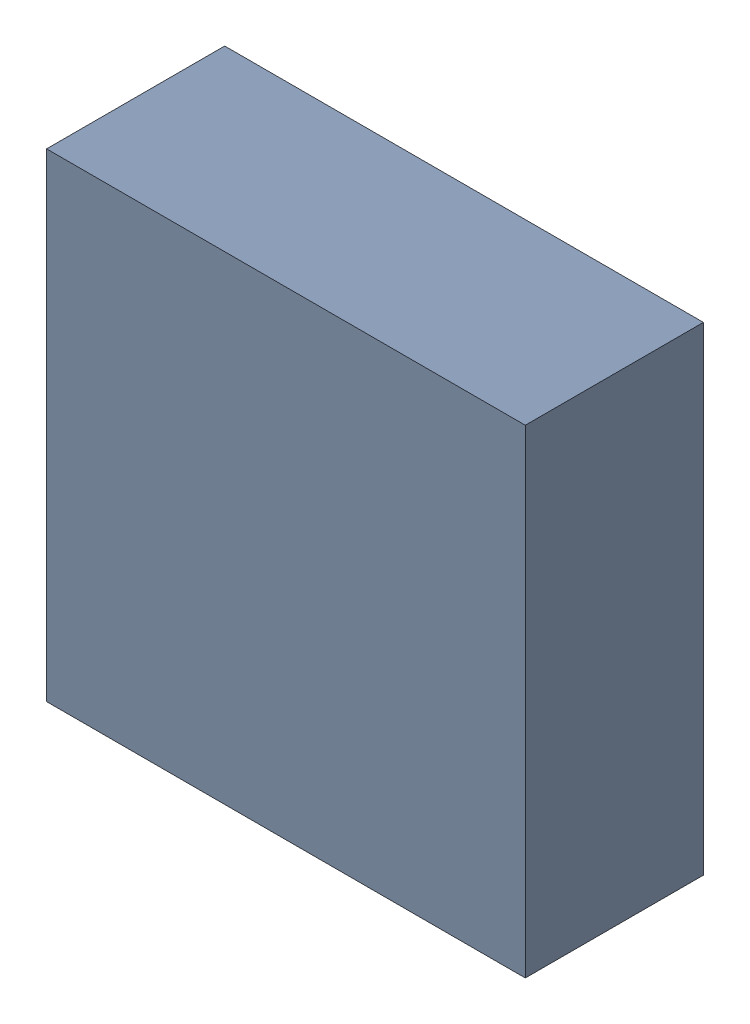
SolidWorks assembly Q8, configuration ﾃﾞﾌｫﾙﾄ. Lengths in mm.
Overall size (2.15 2.15 0.8).
2 component instances, 1 part files, 0 mates.
Components (placement in the parent):
- 689261240-1: 689261240 [ﾃﾞﾌｫﾙﾄ] at (29.5 73.25 0) size (2.15 2.15 0.8)
  - Extruded_30-1: Extruded_30 [ﾃﾞﾌｫﾙﾄ] at origin size (2.15 2.15 0.8)
